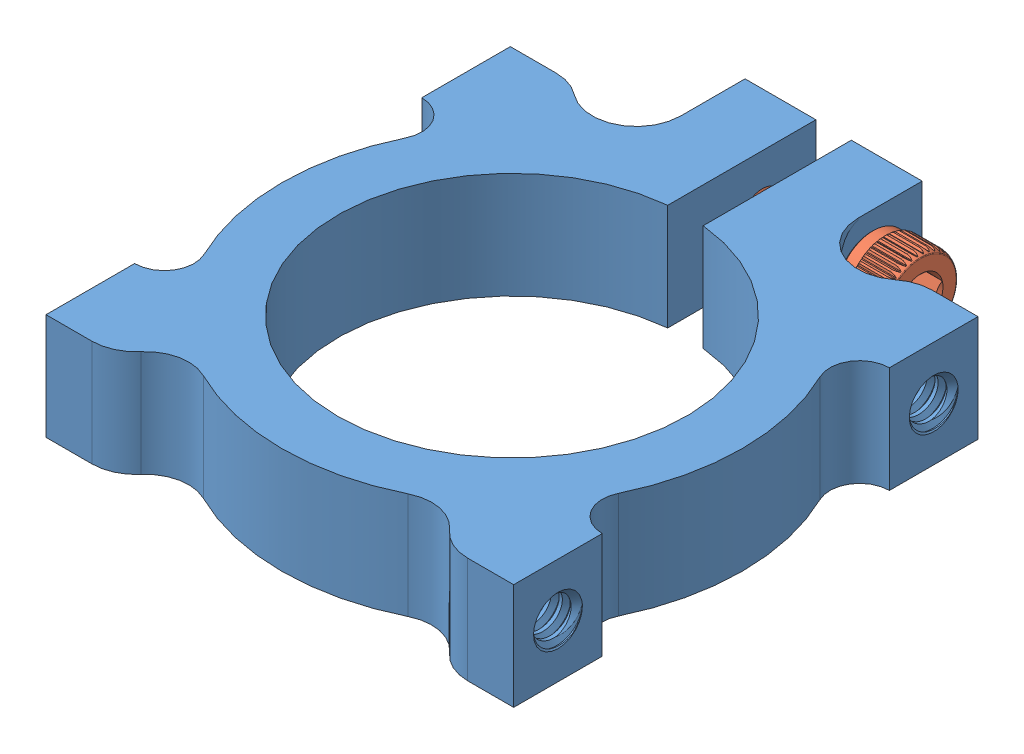
SolidWorks assembly 25m Bore Side Tapped Clamping Mount, configuration Default. Lengths in mm.
Overall size (33.76 11.43 64.42).
2 component instances, 2 part files, 0 mates.
Components (placement in the parent):
- 25m Bore Side Tapped Clamping Mount-1: 25m Bore Side Tapped Clamping Mount [Default] at (0.615 -8.6446 6.1668) size (33.76 7.62 39.7)
- #6-32 0_5 Bolt-1: #6-32 0_5 Bolt [Default] at (-31.135 -4.8346 -13.2719) x (0 0.2706 0.962692) z (-1 0 0) size (5.57 5.57 16.21)
